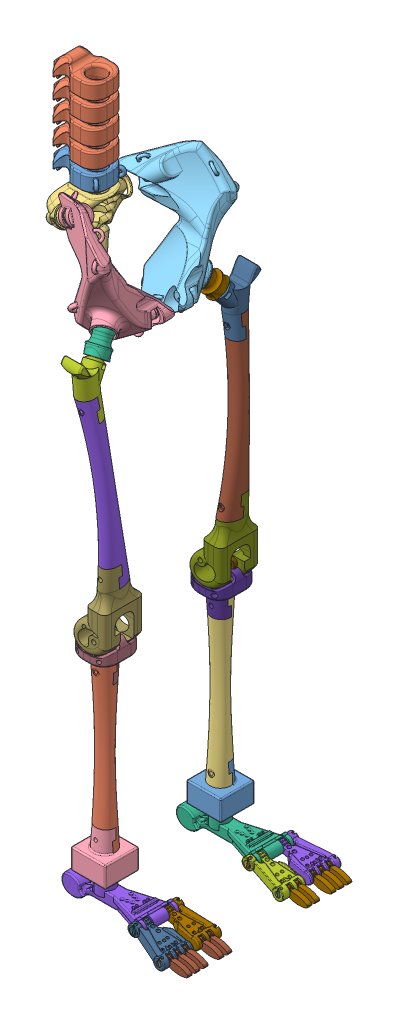
SolidWorks assembly 00_Bipedal_Robot, configuration Default. Lengths in mm.
Overall size (396.98 1225.44 372.82).
76 component instances, 51 part files, 28 mates.
Components (placement in the parent):
- 01_Spine-1: 01_Spine [Default] at (28.9177 1.8135 66.819) size (105.86 206.63 64.14)
  - 01_01_L2.001-1: 01_01_L2.001 [Default] at (41.5865 56.9936 86.3878) size (105.86 60.55 64.14)
  - 01_02_L4_001-1: 01_02_L4_001 [Default] at (41.5865 93.5136 86.3878) size (102.42 60.55 64.14)
  - 01_02_L4_001-4: 01_02_L4_001 [Default] at (41.5865 203.0736 86.3878) size (102.42 60.55 64.14)
  - 01_02_L4_001-2: 01_02_L4_001 [Default] at (41.5865 166.5536 86.3878) size (102.42 60.55 64.14)
  - 01_02_L4_001-3: 01_02_L4_001 [Default] at (41.5865 130.0336 86.3878) size (102.42 60.55 64.14)
- 02_Pelvis-1: 02_Pelvis [Default] at (154.5333 -101.1363 111.1432) x (0 0 1) z (-1 0 0) size (277.43 288.27 328.46)
  - 02_01_SA_001-1: 02_01_SA_001 [Default] at (14.5298 150.5455 116.3104) size (136.19 119.5 78.57)
  - 02_02_IW_R_001-1: 02_02_IW_R_001 [Default] at (111.3644 90.1965 77.2982) x (-0.998975 0.039475 -0.022151) z (0.022938 0.019591 -0.999545) size (224.34 274.02 288.6)
  - 02_03_IW_L_001-1: 02_03_IW_L_001 [Default] at (-27.3049 90.1965 77.2982) x (0.998975 0.039475 -0.022151) z (0.022938 -0.019591 0.999545) size (128.16 237.16 186.34)
- 03_Femur_Right-1: 03_Femur_Right [Default] at (257.7999 81.8146 270.4067) x (0.97624 0.090455 -0.196909) z (-0.088437 0.9959 0.019039) size (86.13 103.13 395.48)
  - 03_01_FK_R_001-1: 03_01_FK_R_001 [Default] at (-102.7139 -439.9992 -170.2167) size (38.14 57.65 59.92)
  - 03_02_FH_R_001-1: 03_02_FH_R_001 [Default] at (-91.5057 2.8278 -226.8625) x (0.97624 -0.197823 -0.088437) z (-0.204043 -0.976609 -0.067832) size (46.92 105.86 63.35)
  - 03_03_FE_R_001-1: 03_03_FE_R_001 [Default] at (-94.0837 16.8723 -532.1934) x (-0.97624 0.197823 0.088437) z (0.204043 0.976609 0.067832) size (54.81 304.92 50.87)
- 04_Femur_Left-1: 04_Femur_Left [Default] at (164.6656 -145.4161 -25.6704) x (-0.938512 0.037119 -0.343245) z (0.033868 0.999307 0.015464) size (101.49 105.42 393.58)
  - 04_01_FK_L_001-1: 04_01_FK_L_001 [Default] at (-46.7228 -402.9121 50.9918) size (38.14 57.65 59.92)
  - 04_02_FH_L_001-1: 04_02_FH_L_001 [Default] at (-71.3735 127.5449 4.2394) x (-0.938512 -0.343581 0.033868) z (-0.338704 0.935293 0.1025) size (46.92 105.86 63.35)
  - 04_03_FE_L_001-1: 04_03_FE_L_001 [Default] at (-110.4217 141.179 -298.5629) x (0.938512 0.343581 -0.033868) z (0.338704 -0.935293 -0.1025) size (54.81 304.92 50.87)
- 05_Knee_Right-1: 05_Knee_Right [Free Rotation] at (200.6195 -627.0361 402.3393) x (-1 0 0) z (0 0 -1) size (80.56 203.36 76.75)
  - 05_01_KT_R_001-1: 05_01_KT_R_001 [Default] at (2.4253 92.434 142.6236) size (74.55 156.7 74.23)
  - 05_02_KB_R_001-1: 05_02_KB_R_001 [Default] at (4.5858 51.316 143.0681) x (0 0 -1) z (1 0 0) size (76.75 80.81 77.22)
  - 05_03_PL_R_001-1: 05_03_PL_R_001 [Default] at (9.5638 75.9954 136.2736) x (0.684095 0.729393 0) z (0 0 1) size (15.95 62.18 6.35)
  - 05_04_AL_R_001-1: 05_04_AL_R_001 [Default] at (-7.1378 73.2962 142.6236) x (0.886446 -0.462832 0) z (0 0 1) size (15.95 67.39 6.35)
- 06_Knee_Left-1: 06_Knee_Left [Free Rotation] at (257.3848 -574.3176 165.9282) x (-1 0 0) z (0 0 -1) size (80.56 203.36 76.75)
  - 06_01_KT_L_001-1: 06_01_KT_L_001 [Default] at (59.1906 39.7155 119.2978) size (74.55 156.7 74.23)
  - 06_02_KB_L_001-1: 06_02_KB_L_001 [Default] at (61.3511 -1.4025 118.5993) x (0 0 -1) z (1 0 0) size (76.75 80.81 77.22)
  - 06_03_PL_L_001-1: 06_03_PL_L_001 [Default] at (66.3291 23.277 119.2978) x (0.684095 0.729393 0) z (0 0 1) size (15.95 62.18 6.35)
  - 06_04_AL_L_001-1: 06_04_AL_L_001 [Default] at (49.6275 20.5777 112.9478) x (0.886446 -0.462832 0) z (0 0 1) size (15.95 67.39 6.35)
- 07_TI_R_001-1: 07_TI_R_001 [Default] at (190.9537 -886.8701 259.2712) x (0 0 1) z (-1 0 0) size (38.19 304.9 38.19)
- 08_TI_L_001-1: 08_TI_L_001 [Default] at (190.9537 -886.8701 47.3288) x (0 0 1) z (-1 0 0) size (38.19 304.9 38.19)
- 09_Foot_Ankle-1: 09_Foot_Ankle [Fully Constrained] at (139.2649 -938.3089 269.8843) x (0 0 -1) z (1 0 0) size (106.69 132.63 259.88)
  - 09_01_AE_R_001-1: 09_01_AE_R_001 [Default] at (-20.5538 13.3388 22.6611) size (62.23 76.2 63.5)
  - 09_02_AM_R_001-1: 09_02_AM_R_001 [Default] at (30.5162 13.8468 51.8711) x (-1 0 0) z (0 0 1) size (40.89 25.02 50.04)
  - 09_03_AI_R_001-1: 09_03_AI_R_001 [Default] at (30.7702 13.8468 51.8711) x (-1 0 0) z (0 0 1) size (45.97 24.51 48.01)
  - 09_04_AB_R_001-1: 09_04_AB_R_001 [Default] at (10.3232 11.3068 37.5281) size (27.55 36.83 34.71)
  - 09_06_FT_R_001-1: 09_06_FT_R_001 [Default] at (24.928 10.5643 16.707) x (0 0 1) z (-1 0 0) size (165.6 39.34 64.86)
  - 09_07_MM_R_001-1: 09_07_MM_R_001 [Default] at (43.58 -18.2815 210.0017) x (-1 0 0) z (0 0.219565 -0.975598) size (43.26 21.17 83.82)
  - 09_08_LM_R_001-1: 09_08_LM_R_001 [Default] at (-21.7787 -23.2375 208.8863) x (1 0 0) z (0 0.219565 -0.975598) size (55.48 21.27 83.82)
  - 09_09_PH_R_001-1: 09_09_PH_R_001 [Default] at (-5.0147 -29.4326 207.4921) x (1 0 0) z (0 -0.152333 0.988329) size (8.13 14.73 49.22)
  - 09_09_PH_R_001-2: 09_09_PH_R_001 [Default] at (23.768 -29.4326 207.4921) x (1 0 0) z (0 -0.152333 0.988329) size (8.13 14.73 49.22)
  - 09_09_PH_R_001-3: 09_09_PH_R_001 [Default] at (-20.0007 -29.4326 207.4921) x (1 0 0) z (0 -0.152333 0.988329) size (8.13 14.73 49.22)
  - 09_09_PH_R_001-4: 09_09_PH_R_001 [Default] at (-34.4787 -29.4326 207.4921) x (1 0 0) z (0 -0.152333 0.988329) size (8.13 14.73 49.22)
  - 09_09_PH_R_001-5: 09_09_PH_R_001 [Default] at (38.246 -29.4326 207.4921) x (1 0 0) z (0 -0.152333 0.988329) size (8.13 14.73 49.22)
  - 09_14_ML_R_001-1: 09_14_ML_R_001 [Default] at (-42.8607 -35.6276 206.0978) x (0 -0.219565 0.975598) z (-1 0 0) size (6.6 12.7 4.83)
  - 09_13_LA_R_001-1: 09_13_LA_R_001 [Default] at (6.1613 -29.4326 207.4921) x (0 0.929388 0.369105) z (0 -0.369105 0.929388) size (7.14 45.47 8.76)
  - 09_10_TA_R_001-1: 09_10_TA_R_001 [Default] at (4.3833 -15.4902 145.5416) x (0 -0.687163 -0.726504) z (0 0.726504 -0.687163) size (12.32 29.21 12.32)
  - 09_11_TL_R_001-1: 09_11_TL_R_001 [Default] at (-27.9844 -24.1633 143.5897) x (1 0 0) z (0 -0.219565 0.975598) size (5.08 17.78 8.76)
  - 09_12_MA_R_001-2: 09_12_MA_R_001 [Default] at (49.676 -29.4326 207.4921) x (0 0.989317 0.145783) z (0 -0.145783 0.989317) size (7.14 30.48 8.76)
  - 09_10_TA_R_001-2: 09_10_TA_R_001 [Default] at (17.418 -15.4902 145.5416) x (0 0.421139 -0.906996) z (0 -0.906996 -0.421139) size (12.32 29.21 12.32)
  - 09_11_TL_R_001-2: 09_11_TL_R_001 [Default] at (49.93 -24.4341 143.3876) x (0.965851 0.056889 -0.252776) z (0.259098 -0.212067 0.942282) size (5.08 17.78 8.76)
  - 09_14_ML_R_001-2: 09_14_ML_R_001 [Default] at (56.026 -36.1419 205.9821) x (0.478376 -0.192812 0.856726) z (-0.878155 -0.105034 0.466702) size (6.6 12.7 4.83)
  - 09_05_AL_R_001-1: 09_05_AL_R_001 [Default] at (9.6964 11.3068 50.4741) x (0 0 1) z (-1 0 0) size (22.86 14.73 2.03)
  - 09_15_FL_R_001-1: 09_15_FL_R_001 [Default] at (10.8874 -8.2512 49.2121) x (1 0 0) z (0 1 0) size (4 12.7 4)
- 10_Foot_Left-1: 10_Foot_Left [Fully Constrained] at (144.4962 -943.9307 75.91) x (0 0 -1) z (1 0 0) size (107.45 132.12 259.88)
  - 10_01_AE_L_001-1: 10_01_AE_L_001 [Default] at (59.7481 18.9606 17.4298) size (62.23 76.2 63.5)
  - 10_02_AM_L_001-1: 10_02_AM_L_001 [Default] at (8.1861 19.4686 46.6398) x (-1 0 0) z (0 0.021281 0.999774) size (40.89 25.02 50.04)
  - 10_03_AI_L_001-1: 10_03_AI_L_001 [Default] at (7.9321 19.4686 46.6398) x (-1 0 0) z (0 0 1) size (45.97 24.51 48.01)
  - 10_04_AB_L_001-1: 10_04_AB_L_001 [Default] at (28.3791 16.9286 32.2888) x (-1 0 0) z (0 0 -1) size (27.55 36.83 34.71)
  - 10_05_AL_L_001-1: 10_05_AL_L_001 [Default] at (29.0059 16.9286 45.2428) x (0 0 1) z (-1 0 0) size (22.86 14.73 2.03)
  - 10_06_FT_L_001-1: 10_06_FT_L_001 [Default] at (13.864 16.6942 10.8278) x (0 0 1) z (-1 0 0) size (165.6 39.34 64.86)
  - 10_07_MM_L_001-1: 10_07_MM_L_001 [Default] at (-5.1691 -12.1517 204.1225) x (-1 0 0) z (0 0.219565 -0.975598) size (43.26 21.17 83.82)
  - 10_08_LM_L_001-1: 10_08_LM_L_001 [Default] at (60.9517 -17.1077 203.0071) x (1 0 0) z (0 0.219565 -0.975598) size (55.48 21.27 83.82)
  - 10_09_PH_L_001-1: 10_09_PH_L_001 [Default] at (-8.2171 -23.3028 201.6128) x (1 0 0) z (0 -0.152333 0.988329) size (8.13 14.73 49.22)
  - 10_09_PH_L_001-2: 10_09_PH_L_001 [Default] at (6.2609 -23.3028 201.6128) x (1 0 0) z (0 -0.152333 0.988329) size (8.13 14.73 49.22)
  - 10_09_PH_L_001-3: 10_09_PH_L_001 [Default] at (36.3137 -23.3028 201.6128) x (1 0 0) z (0 -0.152333 0.988329) size (8.13 14.73 49.22)
  - 10_09_PH_L_001-4: 10_09_PH_L_001 [Default] at (50.7917 -23.3028 201.6128) x (1 0 0) z (0 -0.152333 0.988329) size (8.13 14.73 49.22)
  - 10_09_PH_L_001-5: 10_09_PH_L_001 [Default] at (65.2697 -23.3028 201.6128) x (1 0 0) z (0 -0.152333 0.988329) size (8.13 14.73 49.22)
  - 10_10_TA_L_001-1: 10_10_TA_L_001 [Default] at (34.4087 -9.3604 139.6624) x (0 -0.574498 -0.818506) z (0 -0.818506 0.574498) size (12.32 29.21 12.32)
  - 10_10_TA_L_001-2: 10_10_TA_L_001 [Default] at (-7.8361 -9.3604 139.6624) x (0 -0.402176 0.915562) z (0 0.915562 0.402176) size (12.32 29.21 12.32)
  - 10_11_TL_L_001-1: 10_11_TL_L_001 [Default] at (-11.5191 -17.8134 137.6188) x (1 0 0) z (0 -0.219565 0.975598) size (5.08 17.78 8.76)
  - 10_11_TL_L_001-2: 10_11_TL_L_001 [Default] at (67.3017 -18.0841 137.5579) x (1 0 0) z (0 -0.219565 0.975598) size (5.08 17.78 8.76)
  - 10_12_MA_L_001-1: 10_12_MA_L_001 [Default] at (-11.2651 -23.3028 201.6128) x (0 0.935318 0.353809) z (0 0.353809 -0.935318) size (7.14 30.48 8.76)
  - 10_13_LA_L_001-1: 10_13_LA_L_001 [Default] at (33.0117 -23.3028 201.6128) x (0 -0.968652 0.248421) z (0 0.248421 0.968652) size (7.14 45.47 8.76)
  - 10_14_ML_L_001-1: 10_14_ML_L_001 [Default] at (-17.6151 -29.465 200.226) x (0 -0.219565 0.975598) z (-1 0 0) size (6.6 12.7 4.83)
  - 10_14_ML_L_001-2: 10_14_ML_L_001 [Default] at (82.0337 -29.1887 200.2882) x (0 0.219565 -0.975598) z (1 0 0) size (6.6 12.7 4.83)
  - 10_15_FL_L_001-1: 10_15_FL_L_001 [Default] at (27.9046 -2.1214 31.2728) x (0.910479 0.413554 0) z (0.413554 -0.910479 0) size (4 12.7 4)
Mates (geometry in assembly coordinates):
- Concentric2: concentric anti-aligned: cylinder of 01_Spine-1/01_01_L2wAttachments-1 through (70.5042 113.7471 153.2068) axis (0 -1 0) radius 15.875; cylinder of 02_Pelvis-1/02_01_Sacrum-1 through (70.5042 -5.3781 153.2068) axis (0 1 0) radius 15.875
- Perpendicular1: perpendicular: plane of 01_Spine-1/01_01_L2wAttachments-1 through (94.6342 85.8071 147.226) normal (1 0 0); plane of assembly through (0 0 0) normal (0 0 1)
- Distance1: distance = 9.398 mm anti-aligned: plane of 02_Pelvis-1/02_01_Sacrum-1 through (119.5028 49.4091 125.673) normal (0 1 0); plane of 01_Spine-1/01_01_L2wAttachments-1 through (70.5042 58.8071 147.226) normal (0 -1 0)
- Concentric6: concentric: sphere of 02_Pelvis-1/02_02_R IliumWing-1; sphere of 03_Femur_Right-1/03_01_FK_R_001-1
- Parallel2: parallel anti-aligned: plane of 01_Spine-1 through (28.9177 1.8135 66.819) normal (1 0 0); plane of 02_Pelvis-1 through (154.5333 -101.1363 111.1432) normal (-1 0 0)
- Coincident6: coincident anti-aligned: plane of 03_Femur_Right-1/03_03_FE_R_001-1 through (226.8459 -456.5012 260.1342) normal (0 -0.087156 0.996195); plane of 05_Knee_Right-1/05_01_KT_R_001-1 through (230.9252 -534.0451 253.35) normal (0 0.087156 -0.996195)
- Coincident7: coincident anti-aligned: plane of 03_Femur_Right-1/03_03_FE_R_001-1 through (226.8459 -418.7323 265.5821) normal (0 -0.996195 -0.087156); plane of 05_Knee_Right-1/05_01_KT_R_001-1 through (230.9252 -419.1032 269.8205) normal (0 0.996195 0.087156)
- Coincident8: coincident aligned: cylinder of 03_Femur_Right-1/03_03_FE_R_001-1 through (209.6794 -439.925 289.2408) axis (0 0.087156 -0.996195) radius 3.175; circle of 05_Knee_Right-1/05_01_Knee_Top-1
- Coincident9: coincident anti-aligned: plane of 05_Knee_Right-1/05_02_KB_R_001-1 through (227.5926 -582.0701 255.4093) normal (0 0 1); plane of 07_TI_R_001-1 through (210.05 -582.0701 255.4093) normal (0 0 -1)
- Coincident14: coincident anti-aligned: plane of 05_Knee_Right-1/05_02_KB_R_001-1 through (227.5926 -620.1701 261.7593) normal (0 -1 0); plane of 07_TI_R_001-1 through (210.05 -620.1701 261.7593) normal (0 1 0)
- Concentric7: concentric aligned: cylinder of 05_Knee_Right-1/05_02_KB_R_001-1 through (191.136 -601.1201 240.9313) axis (0 0 1) radius 4.0386; cylinder of 07_TI_R_001-1 through (191.136 -601.1201 240.1747) axis (0 0 1) radius 3.2385
- Concentric8: concentric: sphere of 02_Pelvis-1/02_03_L IliumWing-1; sphere of 04_Femur_Left-1/04_01_FK_L_001-1
- Coincident15: coincident anti-aligned: plane of 04_Femur_Left-1/04_03_FE_L_001-1 through (226.8459 -456.5012 46.2118) normal (0 -0.087156 -0.996195); plane of 06_Knee_Left-1/06_01_KT_L_001-1 through (230.9252 -534.0451 52.996) normal (0 0.087156 0.996195)
- Coincident16: coincident anti-aligned: plane of 04_Femur_Left-1/04_03_FE_L_001-1 through (226.8459 -418.7323 40.7639) normal (0 -0.996195 0.087156); plane of 06_Knee_Left-1/06_01_KT_L_001-1 through (230.9252 -419.1032 36.5255) normal (0 0.996195 -0.087156)
- Concentric9: concentric aligned: cylinder of 04_Femur_Left-1/04_03_FE_L_001-1 through (209.6794 -439.925 17.1052) axis (0 0.087156 0.996195) radius 3.175; cylinder of 06_Knee_Left-1/06_01_KT_L_001-1 through (209.6794 -441.599 -2.0286) axis (0 0.087156 0.996195) radius 3.175
- Coincident17: coincident anti-aligned: plane of 06_Knee_Left-1/06_02_KB_L_001-1 through (227.5926 -582.0701 51.1907) normal (0 0 -1); plane of 08_TI_L_001-1 through (210.05 -582.0701 51.1907) normal (0 0 1)
- Coincident18: coincident anti-aligned: plane of 06_Knee_Left-1/06_02_KB_L_001-1 through (227.5926 -620.1701 44.8407) normal (0 -1 0); plane of 08_TI_L_001-1 through (210.05 -620.1701 44.8407) normal (0 1 0)
- Concentric10: concentric aligned: cylinder of 06_Knee_Left-1/06_02_KB_L_001-1 through (191.136 -601.1201 65.6687) axis (0 0 -1) radius 4.0386; cylinder of 08_TI_L_001-1 through (191.136 -601.1201 66.4253) axis (0 0 -1) radius 3.2385
- Coincident19: coincident anti-aligned: plane of 07_TI_R_001-1 through (210.05 -867.8201 256.7831) normal (0 0 1); plane of 09_Foot_Ankle-1/09_01_AE_R_001-1 through (159.386 -867.8201 256.7831) normal (0 0 -1)
- Coincident20: coincident anti-aligned: plane of 07_TI_R_001-1 through (210.05 -848.7701 256.7831) normal (0 -1 0); plane of 09_Foot_Ankle-1/09_01_AE_R_001-1 through (159.386 -848.7701 278.3731) normal (0 1 0)
- Concentric11: concentric anti-aligned: cylinder of 07_TI_R_001-1 through (191.136 -867.8201 240.1747) axis (0 0 1) radius 3.2385; cylinder of 09_Foot_Ankle-1/09_01_AE_R_001-1 through (191.136 -867.8201 290.4381) axis (0 0 -1) radius 3.2385
- Parallel3: parallel anti-aligned: plane of 09_Foot_Ankle-1 through (139.2649 -977.9015 269.8843) normal (0 -1 0)
- Parallel5: parallel aligned: plane of 09_Foot_Ankle-1 through (139.2649 -938.3089 269.8843) normal (1 0 0)
- Concentric12: concentric anti-aligned: cylinder of 08_TI_L_001-1 through (191.136 -867.8201 66.4253) axis (0 0 -1) radius 3.2385; cylinder of 10_Foot_Left-1/10_01_AE_L_001-1 through (191.136 -867.8201 16.162) axis (0 0 1) radius 3.2385
- Coincident21: coincident anti-aligned: plane of 08_TI_L_001-1 through (210.05 -867.8201 49.817) normal (0 0 -1); plane of 10_Foot_Left-1/10_01_AE_L_001-1 through (159.386 -867.8201 49.817) normal (0 0 1)
- Coincident22: coincident anti-aligned: plane of 08_TI_L_001-1 through (210.05 -848.7701 49.817) normal (0 -1 0); plane of 10_Foot_Left-1/10_01_AE_L_001-1 through (159.386 -848.7701 28.227) normal (0 1 0)
- Parallel6: parallel anti-aligned: plane of 10_Foot_Left-1 through (144.4962 -977.3935 75.91) normal (0 -1 0)
- Parallel7: parallel anti-aligned: plane of 10_Foot_Left-1 through (144.4962 -943.9307 75.91) normal (0 0 -1)
